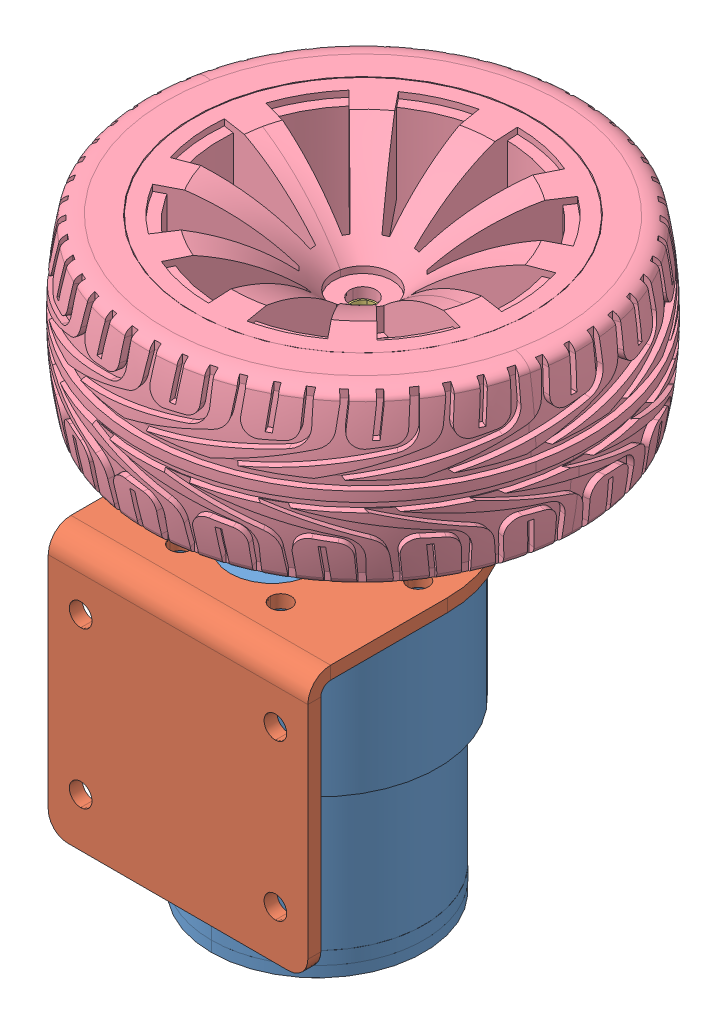
SolidWorks assembly 轮组, configuration 默认. Lengths in mm.
Overall size (89.26 93.4 89.44).
4 component instances, 4 part files, 8 mates.
Components (placement in the parent):
- 520电机-1: 520电机 [默认] at (-84.5599 41.1917 74.8) size (37 74.8 37)
- 520电机支架.step-1: 520电机支架.step [默认] at (-84.5599 44.4417 94.3) x (1 0 0) z (0 1 0) size (40 41.5 40.5)
- 内径6短联轴器-1: 内径6短联轴器 [默认] at (-84.5599 89.6917 67.8) x (-0.864569 0 0.502514) z (0.502514 0 0.864569) size (13.88 18.01 13.88)
- 双色轮毂防滑轮胎.step-1: 双色轮毂防滑轮胎.step [默认] at (-84.5599 89.0417 67.8) x (0 -1 0) z (-0.978747 0 -0.205069) size (26.5 75.59 75.36)
Mates (geometry in assembly coordinates):
- 重合2: coincident: plane of 520电机-1 through (-84.5599 62.6917 74.8) normal (0 1 0); plane of 520电机支架.step-1 through (-84.5599 62.6917 74.8) normal (0 -1 0)
- 同心5: concentric: cylinder of 520电机-1 through (-84.5599 68.6917 67.8) axis (0 -1 0) radius 6; cylinder of 520电机支架.step-1 through (-84.5599 64.6917 67.8) axis (0 -1 0) radius 6.5
- 同心6: concentric anti-aligned: cylinder of 520电机-1 through (-100.0599 59.6917 74.8) axis (0 1 0) radius 1.6; cylinder of 520电机支架.step-1 through (-100.0599 64.6917 74.8) axis (0 -1 0) radius 1.6
- 同心7: concentric aligned: cylinder of 520电机-1 through (-84.5599 83.6917 67.8) axis (0 -1 0) radius 3; cylinder of 内径6短联轴器-1 through (-84.5599 83.6917 67.8) axis (0 -1 0) radius 3
- 同心8: concentric aligned: cylinder of 内径6短联轴器-1 through (-84.5599 71.6917 67.8) axis (0 1 0) radius 5.7; cylinder of 双色轮毂防滑轮胎.step-1 through (-84.5599 75.7792 67.8) axis (0 1 0) radius 2
- 重合3: coincident anti-aligned: plane of 内径6短联轴器-1 through (-84.5599 89.6917 67.8) normal (0 1 0); plane of 双色轮毂防滑轮胎.step-1 through (-84.5599 89.6917 67.8) normal (0 -1 0)
- 重合4: coincident anti-aligned: plane of 内径6短联轴器-1 through (-84.58 79.6917 60.8718) normal (-0.502514 0 -0.864569); plane of 双色轮毂防滑轮胎.step-1 through (-90.5699 89.6917 64.3533) normal (0.502514 0 0.864569)
- 重合5: coincident anti-aligned: plane of 520电机-1 through (-84.5599 83.6917 67.8) normal (0 1 0); plane of 内径6短联轴器-1 through (-84.5599 83.6917 67.8) normal (0 -1 0)
